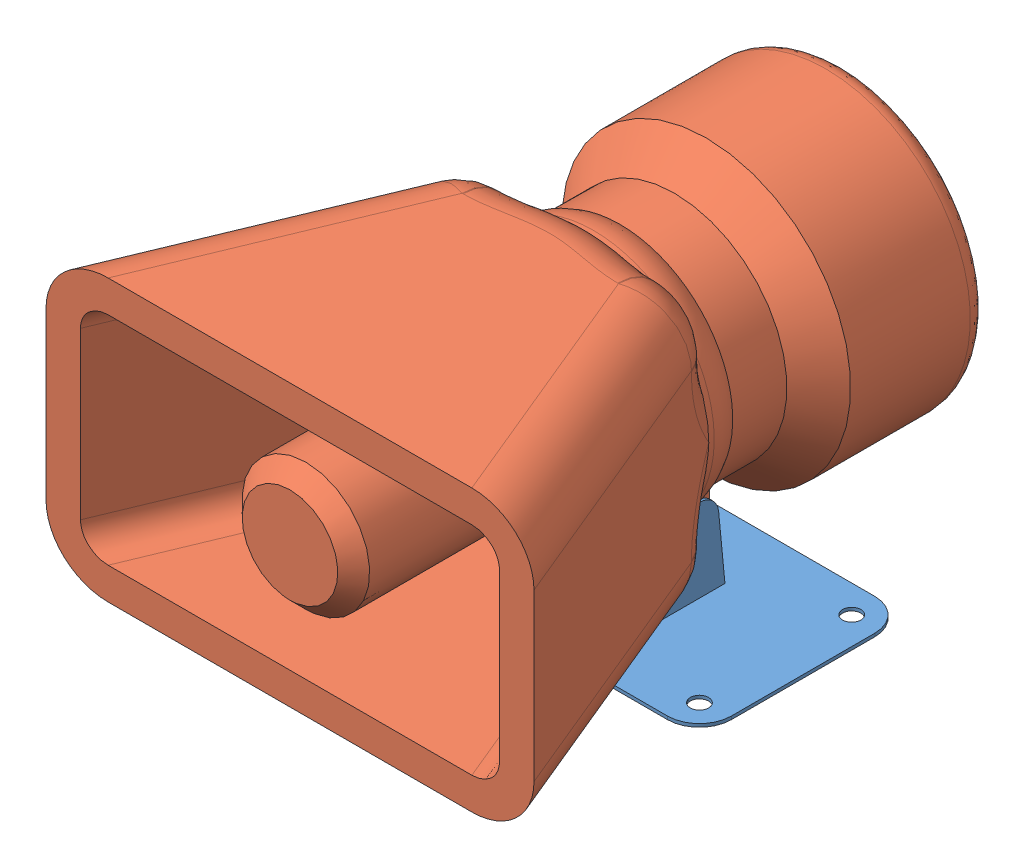
SolidWorks assembly Ensemble Sirenne, configuration Default. Lengths in mm.
Overall size (153 116.43 174).
2 component instances, 2 part files, 3 mates.
Components (placement in the parent):
- Support-1: Support [Default] at (-1.3362 -21.5808 6.1951) size (90 27 65)
- Sirenne-1: Sirenne [Default] at (-1.8362 49.5461 -52.4337) x (0 -1 0) z (0 0 1) size (102.43 153 174)
Mates (geometry in assembly coordinates):
- Coincident1: coincident anti-aligned: circle of Support-1; cylinder of Sirenne-1 through (74.6638 -0.5808 6.1951) axis (-1 0 0) radius 2
- Coincident2: coincident anti-aligned: plane of Support-1 through (5.6638 -21.5808 6.1951) normal (-1 0 0); plane of Sirenne-1 through (5.6638 17.4133 16.5663) normal (1 0 0)
- Parallel1: parallel anti-aligned: line of Support-1 through (6.6638 5.4192 1.6459) axis (0 0 1); line of Sirenne-1 through (5.6638 15.0521 16.5663) axis (0 0 -1)
